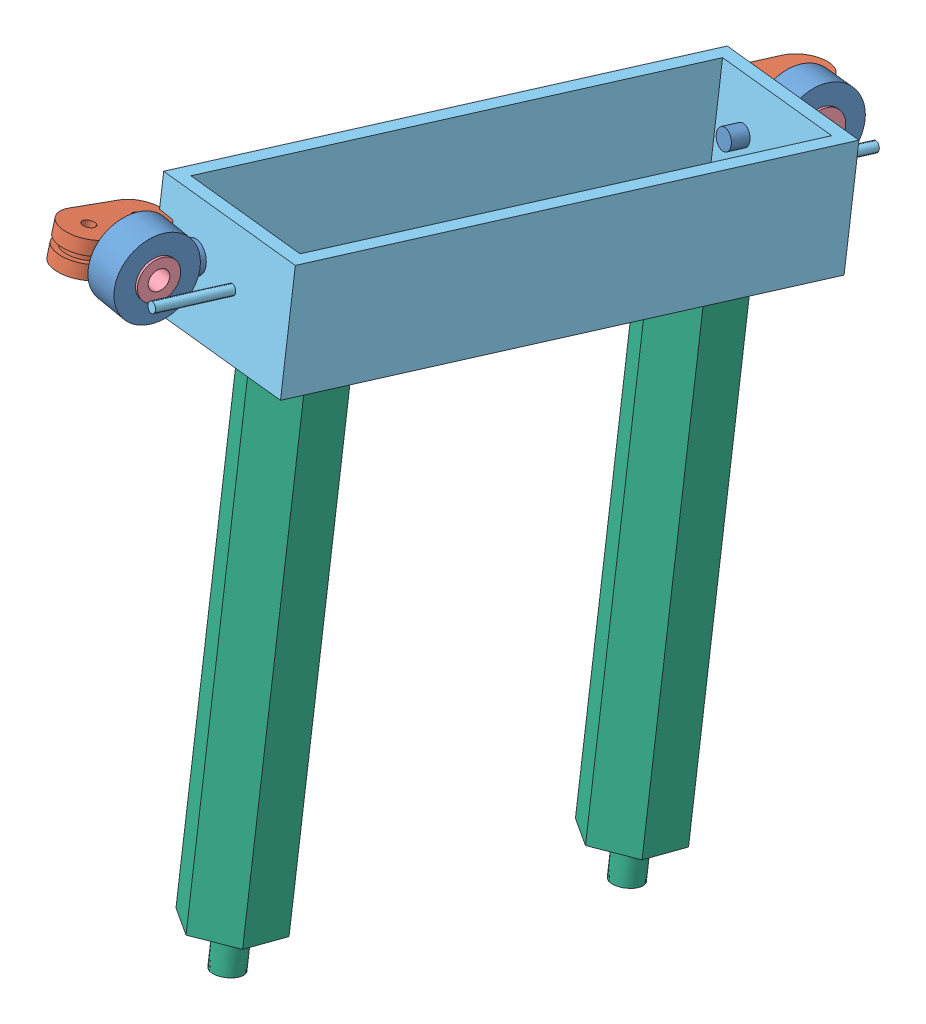
SolidWorks assembly 装配体2, configuration 默认. Lengths in mm.
Overall size (65.06 150.35 145.43).
14 component instances, 7 part files, 23 mates.
Components (placement in the parent):
- 万向绳-2: 万向绳 [默认] at (-110.1959 -74.2307 270.1408) x (-0.015884 -0.985039 0.1716) z (0.182177 -0.1716 -0.968176) size (16 18.5 26.19)
  - 万向绳2-1: 万向绳2 [默认] at (-97.2122 22.5289 -4) size (16 7 24)
  - 万向绳1-1: 万向绳1 [默认] at (-93.4396 35.2789 0.5366) x (-0.058649 0 -0.998279) z (0 1 0) size (20 7 13.5)
  - 万向绳3-1: 万向绳3 [默认] at (-97.2122 27.0289 -4) size (11 2.5 11)
  - 万向绳4-1: 万向绳4 [默认] at (-97.2122 27.0289 -4) x (-0.837169 0 -0.546944) z (-0.546944 0 0.837169) size (8 5 8)
- 出绳点链接板（06.04）-1: 出绳点链接板（06.04） [默认] at (-123.0635 -1.661 194.6409) x (0.182177 -0.1716 -0.968176) z (0.98233 0.074701 0.1716) size (135.6 23 35)
- 万向绳1-1: 万向绳1 [默认] at (-120.3424 -4.5256 126.4067) x (-0.182177 0.1716 0.968176) z (-0.98233 -0.074701 -0.1716) size (20 7 13.5)
- 万向绳2-1: 万向绳2 [默认] at (-108.8331 0.6801 132.5559) x (-0.042877 0.98233 -0.182177) z (-0.182177 0.1716 0.968176) size (16 7 24)
- 万向绳4-1: 万向绳4 [默认] at (-108.342 0.7174 132.6417) x (-0.042877 0.98233 -0.182177) z (-0.182177 0.1716 0.968176) size (8 5 8)
- 万向绳3-1: 万向绳3 [默认] at (-113.2536 0.3439 131.7837) x (-0.042877 0.98233 -0.182177) z (-0.182177 0.1716 0.968176) size (11 2.5 11)
- 单头六角柱100-3: 单头六角柱100 [默认] at (-108.8644 -7.5357 159.6213) x (-0.808017 -0.14134 -0.571954) z (-0.587597 0.122678 0.7998) size (18.48 108 16.01)
- 柱塞螺丝M6-1: 柱塞螺丝M6 [默认] at (-109.1534 -0.9148 158.3935) x (-0.808017 -0.14134 -0.571954) z (-0.587597 0.122678 0.7998) size (12 14.74 12)
- 柱塞螺丝M6-2: 柱塞螺丝M6 [默认] at (-122.6007 11.9716 231.0444) x (-0.808017 -0.14134 -0.571954) z (-0.587597 0.122678 0.7998) size (12 14.74 12)
- 单头六角柱100-4: 单头六角柱100 [默认] at (-122.3117 5.3507 232.2723) x (-0.808017 -0.14134 -0.571954) z (-0.587597 0.122678 0.7998) size (18.48 108 16.01)
Mates (geometry in assembly coordinates):
- 同心2: concentric aligned: cylinder of 万向绳-2/万向绳2-1 through (-132.0557 19.0544 237.0992) axis (-0.182177 0.1716 0.968176) radius 2; cylinder of 出绳点链接板（06.04）-1 through (-113.2004 1.2938 136.893) axis (-0.182177 0.1716 0.968176) radius 2
- 重合4: coincident anti-aligned: plane of 万向绳-2/万向绳2-1 through (-133.2399 20.1698 243.3923) normal (0.182177 -0.1716 -0.968176); plane of 出绳点链接板（06.04）-1 through (-132.8111 10.3465 245.2141) normal (-0.182177 0.1716 0.968176)
- 同心3: concentric anti-aligned: cylinder of 万向绳2-1 through (-113.2536 0.3439 131.7837) axis (-0.98233 -0.074701 -0.1716) radius 5.5; cylinder of 万向绳3-1 through (-115.7095 0.1572 131.3547) axis (0.98233 0.074701 0.1716) radius 5.5
- 重合5: coincident anti-aligned: plane of 万向绳2-1 through (-113.2536 0.3439 131.7837) normal (-0.98233 -0.074701 -0.1716); plane of 万向绳3-1 through (-113.2536 0.3439 131.7837) normal (0.98233 0.074701 0.1716)
- 同心4: concentric aligned: cylinder of 万向绳2-1 through (-115.7095 0.1572 131.3547) axis (0.98233 0.074701 0.1716) radius 4; cylinder of 万向绳4-1 through (-113.2536 0.3439 131.7837) axis (0.98233 0.074701 0.1716) radius 4
- 重合6: coincident anti-aligned: plane of 万向绳4-1 through (-113.2536 0.3439 131.7837) normal (-0.98233 -0.074701 -0.1716); plane of 万向绳3-1 through (-113.2536 0.3439 131.7837) normal (0.98233 0.074701 0.1716)
- 同心5: concentric anti-aligned: cylinder of 万向绳1-1 through (-113.2536 0.3439 131.7837) axis (-0.98233 -0.074701 -0.1716) radius 3.5; cylinder of 万向绳3-1 through (-115.7095 0.1572 131.3547) axis (0.98233 0.074701 0.1716) radius 3.5
- 重合7: coincident anti-aligned: plane of 万向绳1-1 through (-112.2382 -3.9093 127.8224) normal (0.98233 0.074701 0.1716); plane of 万向绳4-1 through (-113.2536 0.3439 131.7837) normal (-0.98233 -0.074701 -0.1716)
- 重合8: coincident anti-aligned: circle of 出绳点链接板（06.04）-1; cylinder of 万向绳2-1 through (-115.1861 3.1642 147.4461) axis (0.182177 -0.1716 -0.968176) radius 2
- 重合9: coincident anti-aligned: plane of 出绳点链接板（06.04）-1 through (-113.5732 -7.7745 142.9747) normal (0.182177 -0.1716 -0.968176); plane of 万向绳2-1 through (-114.002 2.0488 141.1529) normal (-0.182177 0.1716 0.968176)
- 平行4: parallel aligned: plane of 出绳点链接板（06.04）-1 through (-133.0155 0.539 192.3784) normal (-0.98233 -0.074701 -0.1716); plane of 万向绳1-1 through (-125.6197 -2.1673 124.9957) normal (-0.98233 -0.074701 -0.1716)
- 平行5: parallel aligned: plane of 出绳点链接板（06.04）-1 through (-123.0635 -1.661 194.6409) normal (0.042877 -0.98233 0.182177); plane of 万向绳1-1 through (-120.3424 -4.5256 126.4067) normal (0.042877 -0.98233 0.182177)
- 同心6: concentric aligned: cylinder of 出绳点链接板（06.04）-1 through (-109.722 12.1109 155.9778) axis (0.042877 -0.98233 0.182177) radius 4; cylinder of 单头六角柱100-1 through (-59.0224 -48.6298 153.1666) axis (0.042877 -0.98233 0.182177) radius 3
- 同心7: concentric aligned: cylinder of 出绳点链接板（06.04）-1 through (-123.1693 24.9974 228.6287) axis (0.042877 -0.98233 0.182177) radius 4; cylinder of 单头六角柱100-2 through (-43.9808 1.9168 189.2857) axis (0.042877 -0.98233 0.182177) radius 3
- 重合15: coincident anti-aligned: plane of 出绳点链接板（06.04）-1 through (-123.0635 -1.661 194.6409) normal (0.042877 -0.98233 0.182177); plane of 单头六角柱100-2 through (-43.6377 -5.9418 190.7431) normal (-0.042877 0.98233 -0.182177)
- 同心8: concentric anti-aligned: cylinder of 出绳点链接板（06.04）-1 through (-109.722 12.1109 155.9778) axis (0.042877 -0.98233 0.182177) radius 4; cylinder of 柱塞螺丝M6-1 through (-108.5214 -15.3943 161.0787) axis (-0.042877 0.98233 -0.182177) radius 3
- 同心9: concentric anti-aligned: cylinder of 出绳点链接板（06.04）-1 through (-123.1693 24.9974 228.6287) axis (0.042877 -0.98233 0.182177) radius 4; cylinder of 柱塞螺丝M6-2 through (-121.9687 -2.5079 233.7297) axis (-0.042877 0.98233 -0.182177) radius 3
- 重合17: coincident anti-aligned: plane of 出绳点链接板（06.04）-1 through (-123.1922 1.286 194.0944) normal (-0.042877 0.98233 -0.182177); plane of 柱塞螺丝M6-2 through (-122.4403 8.2977 231.7257) normal (0.042877 -0.98233 0.182177)
- 重合18: coincident anti-aligned: plane of 出绳点链接板（06.04）-1 through (-123.1922 1.286 194.0944) normal (-0.042877 0.98233 -0.182177); plane of 柱塞螺丝M6-1 through (-108.993 -4.5887 159.0748) normal (0.042877 -0.98233 0.182177)
- 同心10: concentric aligned: cylinder of 单头六角柱100-3 through (-108.5214 -15.3943 161.0787) axis (-0.042877 0.98233 -0.182177) radius 3; cylinder of 柱塞螺丝M6-1 through (-108.5214 -15.3943 161.0787) axis (-0.042877 0.98233 -0.182177) radius 3
- 重合19: coincident anti-aligned: plane of 出绳点链接板（06.04）-1 through (-123.0635 -1.661 194.6409) normal (0.042877 -0.98233 0.182177); plane of 单头六角柱100-3 through (-108.8644 -7.5357 159.6213) normal (-0.042877 0.98233 -0.182177)
- 同心11: concentric aligned: cylinder of 柱塞螺丝M6-2 through (-121.9687 -2.5079 233.7297) axis (-0.042877 0.98233 -0.182177) radius 3; cylinder of 单头六角柱100-4 through (-121.9687 -2.5079 233.7297) axis (-0.042877 0.98233 -0.182177) radius 3
- 重合20: coincident anti-aligned: plane of 出绳点链接板（06.04）-1 through (-123.0635 -1.661 194.6409) normal (0.042877 -0.98233 0.182177); plane of 单头六角柱100-4 through (-122.3117 5.3507 232.2723) normal (-0.042877 0.98233 -0.182177)
